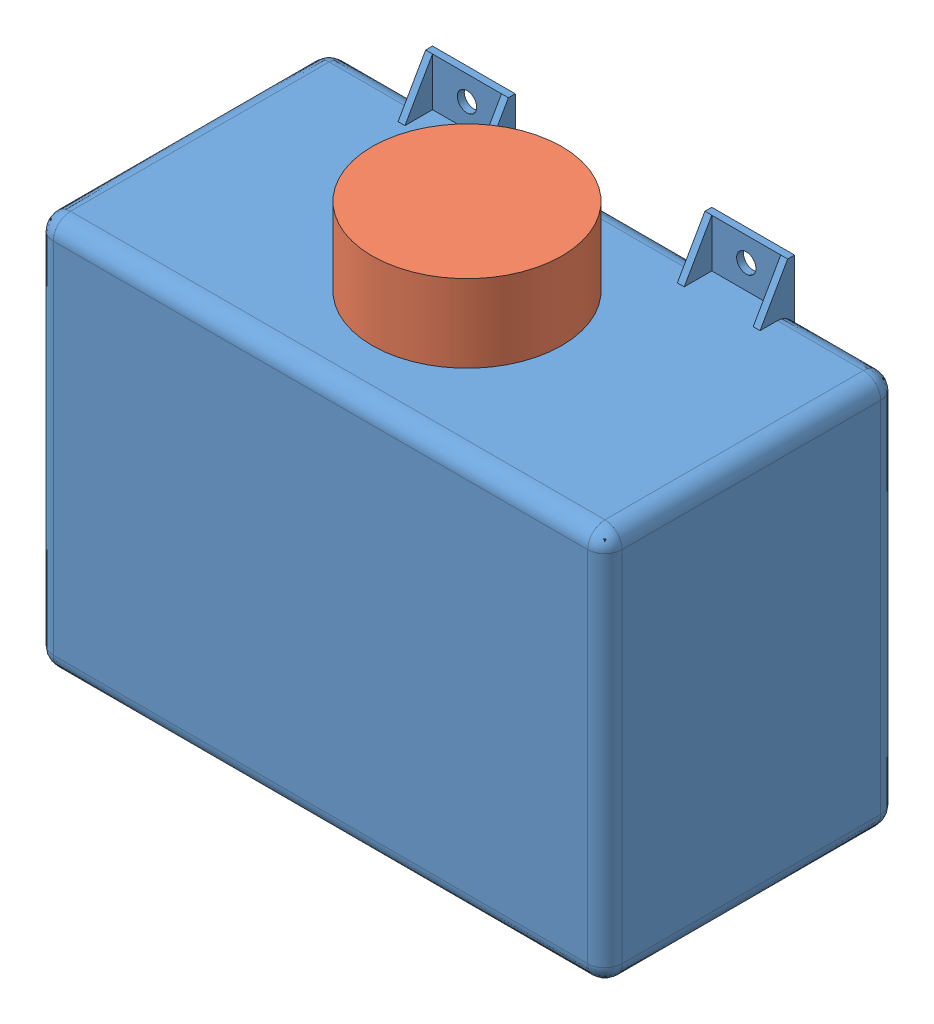
SolidWorks assembly Expansion Tank Subassembly, configuration Default. Lengths in mm.
Overall size (158.75 186.06 106.17).
2 component instances, 2 part files, 8 mates.
Components (placement in the parent):
- EN-00055-AB-Expansion Tank-1: EN-00055-AB-Expansion Tank [Default] at origin size (158.75 182.88 106.17)
- EN-00056-Expansion Tank Cap-1: EN-00056-Expansion Tank Cap [Default] at (0 127 0) x (1 0 0) z (0 1 0) size (57.15 57.15 28.57)
Mates (geometry in assembly coordinates):
- InPlace1: in place: plane of EN-00055-AB-Expansion Tank-1 through (104.775 144.78 -53.975) normal (0 0 -1); plane of ? through (0 0 -53.975) normal (0 0 -1); moOrthogonalPlaneRef_w of EN-00055-AB-Expansion Tank-1 through (104.775 144.78 -53.975) normal (0 0 -1); plane of ? through (0 0 -53.975) normal (0 1 0); plane of EN-00055-AB-Expansion Tank-1 through (104.775 144.78 -53.975) normal (0 0 -1); plane of ? through (0 0 -53.975) normal (-1 0 0); plane of EN-00055-AB-Expansion Tank-1 through (79.375 127 -53.086) normal (0 0 -1); unknown of ?
- Coincident1: coincident aligned: plane of EN-00055-AB-Expansion Tank-1; plane of ?
- Coincident2: coincident aligned: moOrthogonalPlaneRef_w of EN-00055-AB-Expansion Tank-1 through (0 0 -53.086) normal (0 1 0); plane of EN-00301-Expansion Tank Mounting Tab-1 through (0 0 -53.975) normal (0 1 0)
- Coincident3: coincident anti-aligned: moOrthogonalPlaneRef_w of EN-00055-AB-Expansion Tank-1 through (0 0 -53.086) normal (1 0 0); plane of EN-00301-Expansion Tank Mounting Tab-1 through (0 0 -53.975) normal (-1 0 0)
- InPlace2: in place: plane of EN-00055-AB-Expansion Tank-1 through (0 144.78 0) normal (0 1 0); plane of ? through (0 144.78 0) normal (0 1 0); plane of EN-00055-AB-Expansion Tank-1 through (0 144.78 0) normal (0 1 0); plane of ? through (0 144.78 0) normal (0 0 -1); plane of EN-00055-AB-Expansion Tank-1 through (0 144.78 0) normal (0 1 0); plane of ? through (0 144.78 0) normal (1 0 0); plane of EN-00055-AB-Expansion Tank-1 through (0 127 0) normal (0 1 0); unknown of EN-00056-Expansion Tank Cap-1
- Coincident4: coincident aligned: plane of EN-00055-AB-Expansion Tank-1; plane of EN-00056-Expansion Tank Cap-1
- Coincident5: coincident aligned: moOrthogonalPlaneRef_w of EN-00055-AB-Expansion Tank-1 through (0 127 0) normal (0 0 -1); plane of EN-00056-Expansion Tank Cap-1 through (0 127 0) normal (0 0 -1)
- Coincident6: coincident anti-aligned: moOrthogonalPlaneRef_w of EN-00055-AB-Expansion Tank-1 through (0 127 0) normal (-1 0 0); plane of EN-00056-Expansion Tank Cap-1 through (0 127 0) normal (1 0 0)
